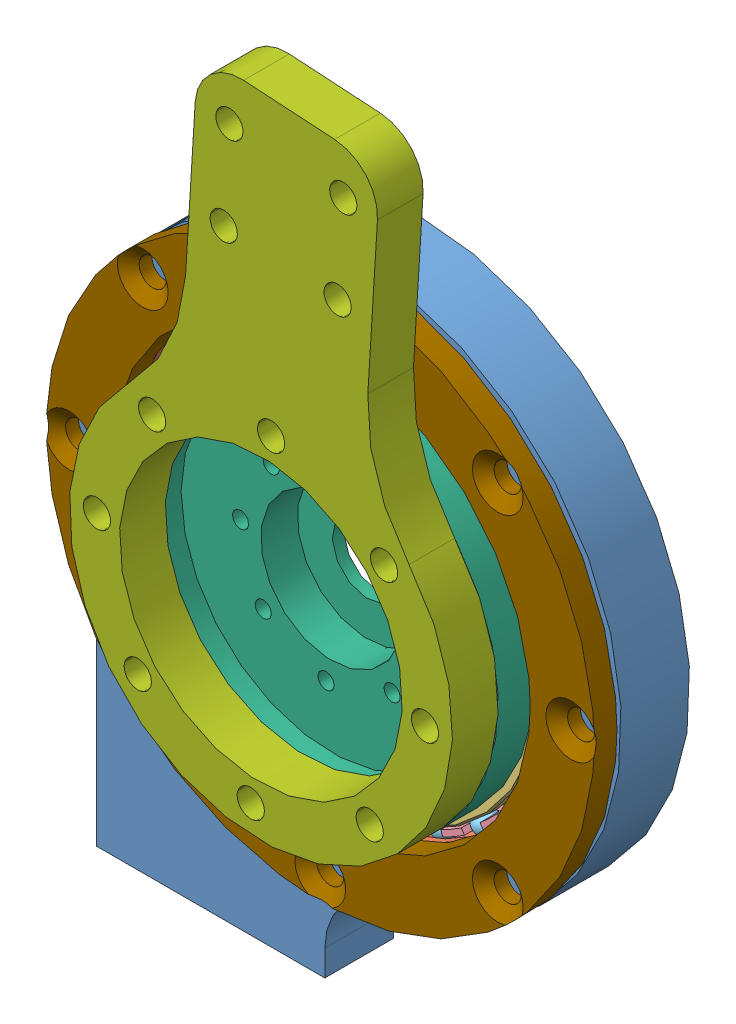
SolidWorks assembly shoulder-bearing-half-other, configuration otherside. Lengths in mm.
Overall size (78.52 115.83 21.59).
37 component instances, 9 part files, 14 mates.
Components (placement in the parent):
- a01-shoulder-base-1: a01-shoulder-base [otherside] at origin size (76.2 88.9 6.35)
- SW3dPS partNO- -KA020AR0-1: SW3dPS partNO- -KA020AR0 [KA020CP0] at (0 0 7.3406) x (-1 0 0) z (0 -1 0) size (63.5 6.35 63.5)
  - SW3dPS-KA - Radial Contact_KA OUTER CATALOG-1: SW3dPS-KA - Radial Contact_KA OUTER CATALOG [KA020002] at origin size (63.5 6.35 63.5)
  - SW3dPS-KA - Radial Contact_KA INNER CATALOG-1: SW3dPS-KA - Radial Contact_KA INNER CATALOG [KA020003] at origin size (55.52 6.35 55.52)
  - SW3dPS-KA - Radial Contact_KA SEPARATOR SAMPLE-1: SW3dPS-KA - Radial Contact_KA SEPARATOR SAMPLE [KA020] at origin size (60.31 5.28 60.41)
    - SW3dPS-KA - Radial Contact_KA SEPARATOR SAMPLE-1: SW3dPS-KA - Radial Contact_KA SEPARATOR SAMPLE [02510020] at origin size (57.94 5.28 57.94)
    - SW3dPS-KA - Radial Contact_KA BALL-1: SW3dPS-KA - Radial Contact_KA BALL [KA020] at origin size (3.17 3.17 3.17)
    - SW3dPS-KA - Radial Contact_KA BALL-2: SW3dPS-KA - Radial Contact_KA BALL [KA020] x (0.973045 0 0.230616) z (-0.230616 0 0.973045) size (3.17 3.17 3.17)
    - SW3dPS-KA - Radial Contact_KA BALL-3: SW3dPS-KA - Radial Contact_KA BALL [KA020] x (0.893633 0 0.448799) z (-0.448799 0 0.893633) size (3.17 3.17 3.17)
    - SW3dPS-KA - Radial Contact_KA BALL-4: SW3dPS-KA - Radial Contact_KA BALL [KA020] x (0.766044 0 0.642788) z (-0.642788 0 0.766044) size (3.17 3.17 3.17)
    - SW3dPS-KA - Radial Contact_KA BALL-5: SW3dPS-KA - Radial Contact_KA BALL [KA020] x (0.597159 0 0.802123) z (-0.802123 0 0.597159) size (3.17 3.17 3.17)
    - SW3dPS-KA - Radial Contact_KA BALL-6: SW3dPS-KA - Radial Contact_KA BALL [KA020] x (0.39608 0 0.918216) z (-0.918216 0 0.39608) size (3.17 3.17 3.17)
    - SW3dPS-KA - Radial Contact_KA BALL-7: SW3dPS-KA - Radial Contact_KA BALL [KA020] x (0.173648 0 0.984808) z (-0.984808 0 0.173648) size (3.17 3.17 3.17)
    - SW3dPS-KA - Radial Contact_KA BALL-8: SW3dPS-KA - Radial Contact_KA BALL [KA020] x (-0.058145 0 0.998308) z (-0.998308 0 -0.058145) size (3.17 3.17 3.17)
    - SW3dPS-KA - Radial Contact_KA BALL-9: SW3dPS-KA - Radial Contact_KA BALL [KA020] x (-0.286803 0 0.95799) z (-0.95799 0 -0.286803) size (3.17 3.17 3.17)
    - SW3dPS-KA - Radial Contact_KA BALL-10: SW3dPS-KA - Radial Contact_KA BALL [KA020] x (-0.5 0 0.866025) z (-0.866025 0 -0.5) size (3.17 3.17 3.17)
    - SW3dPS-KA - Radial Contact_KA BALL-11: SW3dPS-KA - Radial Contact_KA BALL [KA020] x (-0.686242 0 0.727374) z (-0.727374 0 -0.686242) size (3.17 3.17 3.17)
    - SW3dPS-KA - Radial Contact_KA BALL-12: SW3dPS-KA - Radial Contact_KA BALL [KA020] x (-0.835488 0 0.549509) z (-0.549509 0 -0.835488) size (3.17 3.17 3.17)
    - SW3dPS-KA - Radial Contact_KA BALL-13: SW3dPS-KA - Radial Contact_KA BALL [KA020] x (-0.939693 0 0.34202) z (-0.34202 0 -0.939693) size (3.17 3.17 3.17)
    - SW3dPS-KA - Radial Contact_KA BALL-14: SW3dPS-KA - Radial Contact_KA BALL [KA020] x (-0.993238 0 0.116093) z (-0.116093 0 -0.993238) size (3.17 3.17 3.17)
    - SW3dPS-KA - Radial Contact_KA BALL-15: SW3dPS-KA - Radial Contact_KA BALL [KA020] x (-0.993238 0 -0.116093) z (0.116093 0 -0.993238) size (3.17 3.17 3.17)
    - SW3dPS-KA - Radial Contact_KA BALL-16: SW3dPS-KA - Radial Contact_KA BALL [KA020] x (-0.939693 0 -0.34202) z (0.34202 0 -0.939693) size (3.17 3.17 3.17)
    - SW3dPS-KA - Radial Contact_KA BALL-17: SW3dPS-KA - Radial Contact_KA BALL [KA020] x (-0.835488 0 -0.549509) z (0.549509 0 -0.835488) size (3.17 3.17 3.17)
    - SW3dPS-KA - Radial Contact_KA BALL-18: SW3dPS-KA - Radial Contact_KA BALL [KA020] x (-0.686242 0 -0.727374) z (0.727374 0 -0.686242) size (3.17 3.17 3.17)
    - SW3dPS-KA - Radial Contact_KA BALL-19: SW3dPS-KA - Radial Contact_KA BALL [KA020] x (-0.5 0 -0.866025) z (0.866025 0 -0.5) size (3.17 3.17 3.17)
    - SW3dPS-KA - Radial Contact_KA BALL-20: SW3dPS-KA - Radial Contact_KA BALL [KA020] x (-0.286803 0 -0.95799) z (0.95799 0 -0.286803) size (3.17 3.17 3.17)
    - SW3dPS-KA - Radial Contact_KA BALL-21: SW3dPS-KA - Radial Contact_KA BALL [KA020] x (-0.058145 0 -0.998308) z (0.998308 0 -0.058145) size (3.17 3.17 3.17)
    - SW3dPS-KA - Radial Contact_KA BALL-22: SW3dPS-KA - Radial Contact_KA BALL [KA020] x (0.173648 0 -0.984808) z (0.984808 0 0.173648) size (3.17 3.17 3.17)
    - SW3dPS-KA - Radial Contact_KA BALL-23: SW3dPS-KA - Radial Contact_KA BALL [KA020] x (0.39608 0 -0.918216) z (0.918216 0 0.39608) size (3.17 3.17 3.17)
    - SW3dPS-KA - Radial Contact_KA BALL-24: SW3dPS-KA - Radial Contact_KA BALL [KA020] x (0.597159 0 -0.802123) z (0.802123 0 0.597159) size (3.17 3.17 3.17)
    - SW3dPS-KA - Radial Contact_KA BALL-25: SW3dPS-KA - Radial Contact_KA BALL [KA020] x (0.766044 0 -0.642788) z (0.642788 0 0.766044) size (3.17 3.17 3.17)
    - SW3dPS-KA - Radial Contact_KA BALL-26: SW3dPS-KA - Radial Contact_KA BALL [KA020] x (0.893633 0 -0.448799) z (0.448799 0 0.893633) size (3.17 3.17 3.17)
    - SW3dPS-KA - Radial Contact_KA BALL-27: SW3dPS-KA - Radial Contact_KA BALL [KA020] x (0.973045 0 -0.230616) z (0.230616 0 0.973045) size (3.17 3.17 3.17)
- a12-inside-bearing-bottom-1: a12-inside-bearing-bottom [Default] at (0 0 15.24) x (0 0 1) z (-0.061832 -0.998087 0) size (10.16 53.34 53.34)
- a04-shoulder-output-1: a04-shoulder-output [Default] at (0 0 21.59) x (0.998087 -0.061832 0) z (0 0 -1)
- a08-innerbearing-ring-1: a08-innerbearing-ring [Default] at (0 0 3.81) x (-0.662032 0.749475 0) z (0 0 -1)
- a07-outerbearing-ring-1: a07-outerbearing-ring [Default] at (0 0 10.16)
Mates (geometry in assembly coordinates):
- Coincident1: coincident anti-aligned: plane of a01-shoulder-base-1; plane of SW3dPS partNO- -KA020AR0-1/SW3dPS-KA - Radial Contact_KA OUTER CATALOG-1
- Concentric1: concentric aligned: cylinder of a01-shoulder-base-1; cylinder of ?
- Coincident2: coincident anti-aligned: plane of ?; plane of a12-inside-bearing-bottom-1 through (-26.619 1.649 10.16) normal (0 0 -1)
- Concentric2: concentric anti-aligned: cylinder of ?; cylinder of a12-inside-bearing-bottom-1
- Concentric3: concentric aligned: cylinder of a12-inside-bearing-bottom-1; cylinder of a04-shoulder-output-1
- Coincident3: coincident anti-aligned: plane of a12-inside-bearing-bottom-1 through (-20.9149 1.2957 15.24) normal (0 0 1); plane of a04-shoulder-output-1 through (0 0 15.24) normal (0 0 -1)
- Parallel1: parallel anti-aligned: plane of a01-shoulder-base-1; plane of ?
- Concentric4: concentric aligned: cylinder of a12-inside-bearing-bottom-1; cylinder of a04-shoulder-output-1
- Concentric5: concentric aligned: cylinder of a12-inside-bearing-bottom-1; cylinder of a08-innerbearing-ring-1
- Concentric6: concentric aligned: cylinder of a12-inside-bearing-bottom-1; cylinder of a08-innerbearing-ring-1
- Concentric7: concentric aligned: cylinder of a01-shoulder-base-1; cylinder of a07-outerbearing-ring-1
- Coincident4: coincident anti-aligned: plane of a07-outerbearing-ring-1 through (0 0 10.16) normal (0 0 -1); plane of ?
- Coincident5: coincident anti-aligned: plane of SW3dPS partNO- -KA020AR0-1/SW3dPS-KA - Radial Contact_KA OUTER CATALOG-1; plane of a08-innerbearing-ring-1 through (0 0 3.81) normal (0 0 1)
- Concentric8: concentric aligned: cylinder of a01-shoulder-base-1; cylinder of a07-outerbearing-ring-1
